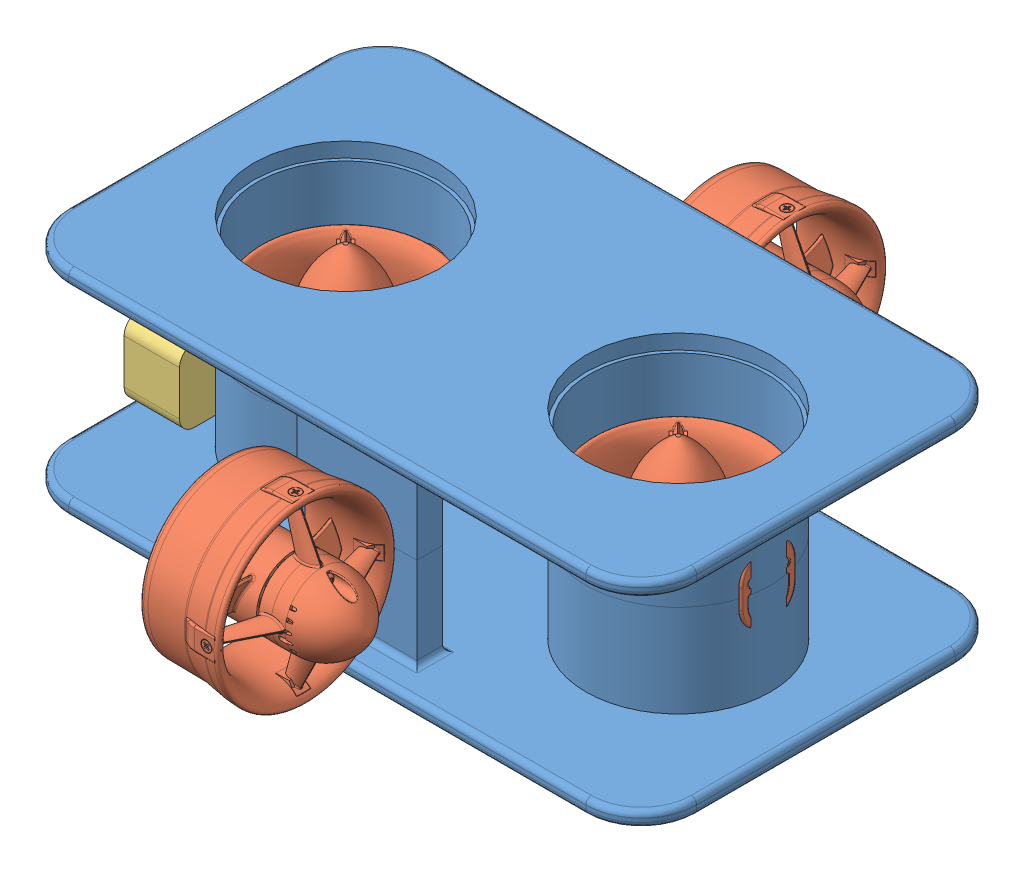
SolidWorks assembly Assem1, configuration Default. Lengths in mm.
Overall size (345 116 362.71).
7 component instances, 3 part files, 22 mates.
Components (placement in the parent):
- cage-1: cage [Default] at (0 58 0) x (-1 0 0) z (0 0 1) size (340 58 200)
- cage-2: cage [Default] at (0 -58 0) size (340 58 200)
- Thruster-T100-1: Thruster-T100 [Default] at (0 0 133) x (0 -1 0) z (-1 0 0) size (96.71 97.51 100.86)
- Thruster-T100-2: Thruster-T100 [Default] at (-90 0 0) x (-1 0 0) z (0 1 0) size (96.71 97.51 100.86)
- Thruster-T100-3: Thruster-T100 [Default] at (90 0 0) x (0 0 -1) z (0 1 0) size (96.71 97.51 100.86)
- Thruster-T100-4: Thruster-T100 [Default] at (0 0 -133) x (0 1 0) z (-1 0 0) size (96.71 97.51 100.86)
- camera-1: camera [Default] at (-155 -30 0) size (35 40 80)
Mates (geometry in assembly coordinates):
- Coincident2: coincident aligned: plane of cage-1 through (0 58 0) normal (0 0 1)
- Distance1: distance = 58 mm anti-aligned: plane of cage-1 through (0 58 0) normal (0 -1 0)
- Coincident4: coincident anti-aligned: plane of cage-1 through (0 58 0) normal (-1 0 0)
- Coincident5: coincident aligned: plane of cage-2 through (0 -58 0) normal (0 0 1)
- Coincident6: coincident aligned: plane of cage-2 through (0 -58 0) normal (1 0 0)
- Coincident8: coincident aligned: plane of cage-2 through (0 0 0) normal (0 1 0)
- Coincident9: coincident anti-aligned: plane of Thruster-T100-1 through (0 0 133) normal (-1 0 0)
- Parallel1: parallel aligned: plane of Thruster-T100-1 through (0 0 133) normal (0 0 1)
- Coincident11: coincident anti-aligned: plane of Thruster-T100-1 through (0 0 133) normal (0 -1 0)
- Coincident12: coincident anti-aligned: plane of cage-1 through (32.5 0 84) normal (0 0 1); plane of Thruster-T100-1 through (-5.2518 0 84) normal (0 0 -1)
- Coincident17: coincident anti-aligned: plane of Thruster-T100-4 through (0 0 -133) normal (-1 0 0)
- Coincident18: coincident anti-aligned: plane of cage-1 through (32.5 0 -84) normal (0 0 -1); plane of Thruster-T100-4 through (-5.2518 0 -84) normal (0 0 1)
- Coincident19: coincident aligned: plane of Thruster-T100-4 through (0 0 -133) normal (0 1 0)
- Coincident20: coincident aligned: plane of Thruster-T100-2 through (-90 0 0) normal (0 1 0)
- Coincident21: coincident aligned: plane of Thruster-T100-2 through (-90 0 0) normal (0 0 1)
- Distance3: distance = 90 mm anti-aligned: plane of Thruster-T100-2 through (-90 0 0) normal (-1 0 0)
- Coincident23: coincident aligned: plane of Thruster-T100-3 through (90 0 0) normal (0 1 0)
- Coincident24: coincident anti-aligned: plane of Thruster-T100-3 through (90 0 0) normal (0 0 -1)
- Distance4: distance = 90 mm anti-aligned: plane of Thruster-T100-3 through (90 0 0) normal (-1 0 0)
- Coincident25: coincident anti-aligned: plane of cage-2 through (-140 -50 70) normal (0 1 0); plane of camera-1 through (-140 -50 40) normal (0 -1 0)
- Tangent1: tangent anti-aligned: cylinder of cage-2 through (-90 0 0) axis (0 -1 0) radius 50; plane of camera-1 through (-140 -30 0) normal (1 0 0)
- Coincident26: coincident aligned: plane of camera-1 through (-155 -30 0) normal (0 0 1)
